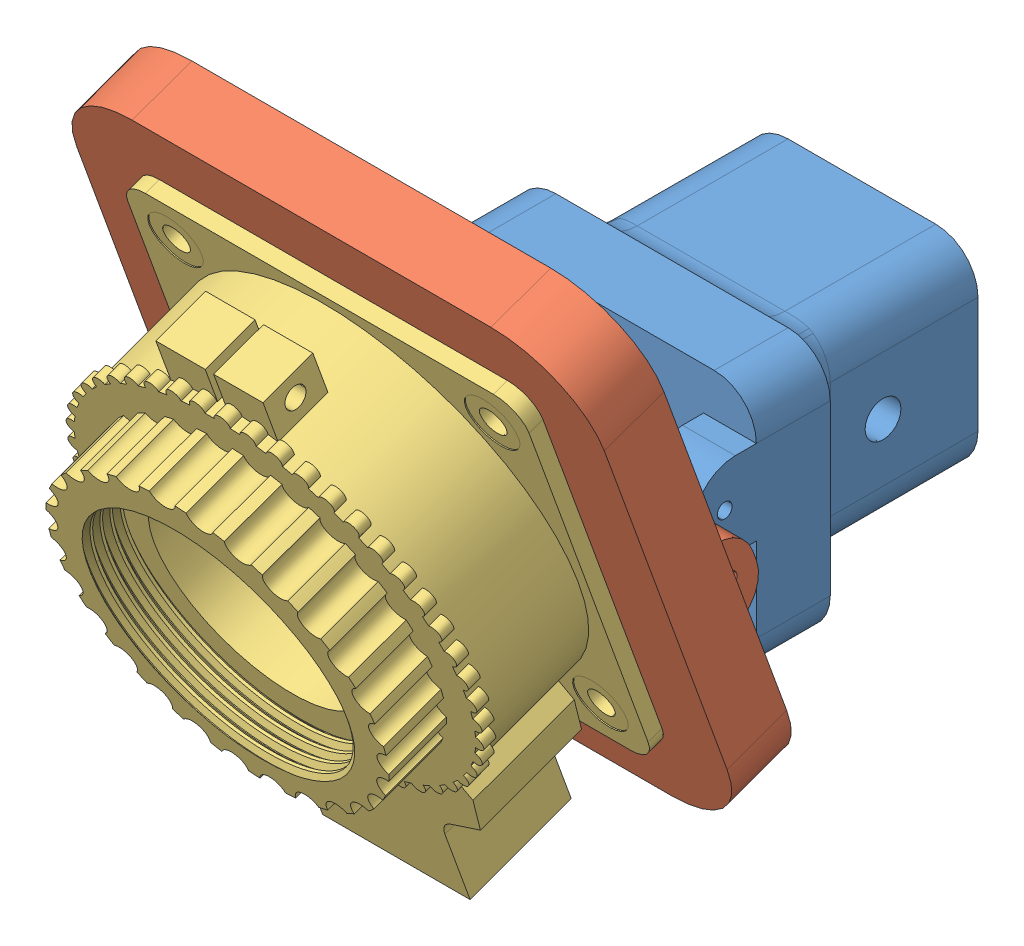
SolidWorks assembly CAMERA_ASSEMBLY, configuration Default. Lengths in mm.
Overall size (50 62.53 68.48).
3 component instances, 3 part files, 8 mates.
Components (placement in the parent):
- New_CAM-Mount-1: New_CAM-Mount [Default] at origin size (30 24 31)
- Camera_Plate-4: Camera_Plate [Default] at (0.05 10.7075 20.0015) x (0 -0.34202 0.939693) z (-1 0 0) size (12 50 50)
- Raspberry Pi HQ Camera-1: Raspberry Pi HQ Camera [Default] at (-18.95 26.5095 32.138) x (1 0 0) z (0 -0.939693 -0.34202) size (38 20.12 51.85)
Mates (geometry in assembly coordinates):
- Coincident1: coordinate: point of New_CAM-Mount-1
- Coincident2: coincident aligned: circle of New_CAM-Mount-1; circle of Camera_Plate-1
- Coincident5: coincident anti-aligned: plane of New_CAM-Mount-1 through (-3 -12 13) normal (-1 0 0); plane of Camera_Plate-4 through (-3 -9.5559 5.2482) normal (1 0 0)
- Coincident6: coincident anti-aligned: circle of New_CAM-Mount-1; circle of Camera_Plate-4
- Concentric1: concentric anti-aligned: circle of Camera_Plate-4; circle of Raspberry Pi HQ Camera-1
- Parallel2: parallel aligned: line of Camera_Plate-4 through (17.05 24.5188 43.7569) axis (-1 0 0); line of Raspberry Pi HQ Camera-1 through (16.55 18.8009 41.4622) axis (-1 0 0)
- Coincident8: coincident anti-aligned: plane of Camera_Plate-4 through (0.05 4.04 29.4175) normal (0 -0.573576 0.819152); plane of Raspberry Pi HQ Camera-1 through (0.05 4.04 29.4175) normal (0 0.573576 -0.819152)
- Angle1: planar angle = 0.349066 rad aligned: line of New_CAM-Mount-1 through (15 -8 7) axis (0 1 0); line of Camera_Plate-4 through (25.05 -5.2673 14.1872) axis (0 0.939693 0.34202)
